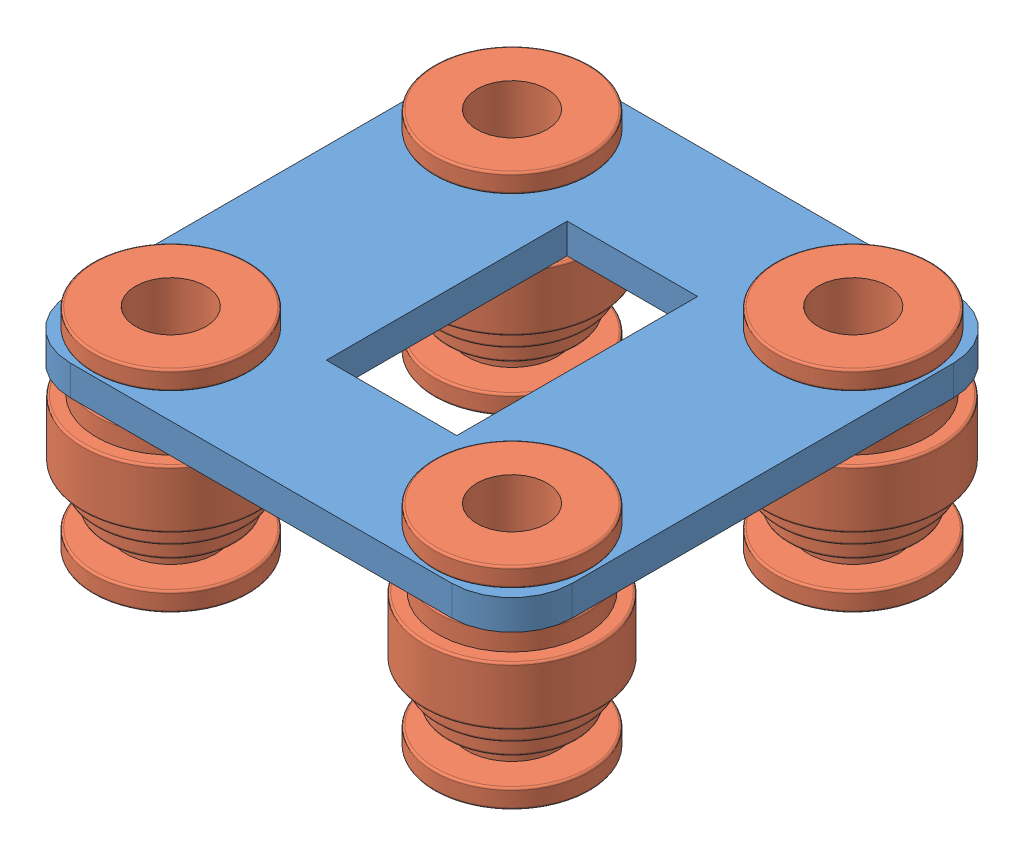
SolidWorks assembly gimbal mount, configuration Default. Lengths in mm.
Overall size (51.5 21 51.5).
5 component instances, 2 part files, 2 mates.
Components (placement in the parent):
- gimbal plate-1: gimbal plate [Default] at (8.1746 31.3476 58.8114) size (50 3 50)
- gimbal damper-1: gimbal damper [Default] at (-8.8254 24.2476 41.8114) size (17.5 21 17.5)
- gimbal damper-2: gimbal damper [Default] at (-8.8254 24.2476 75.8114) size (17.5 21 17.5)
- gimbal damper-3: gimbal damper [Default] at (25.1746 24.2476 41.8114) x (-1 0 0) z (0 0 -1) size (17.5 21 17.5)
- gimbal damper-4: gimbal damper [Default] at (25.1746 24.2476 75.8114) x (-1 0 0) z (0 0 -1) size (17.5 21 17.5)
Mates (geometry in assembly coordinates):
- Coincident1: coincident anti-aligned: plane of gimbal plate-1 through (8.1746 32.8476 58.8114) normal (0 1 0); plane of gimbal damper-1 through (-4.3254 32.8476 41.8114) normal (0 -1 0)
- Concentric1: concentric anti-aligned: cylinder of gimbal plate-1 through (-8.8254 14.9984 41.8114) axis (0 1 0) radius 5.25; cylinder of gimbal damper-1 through (-8.8254 31.7476 41.8114) axis (0 -1 0) radius 3.5
